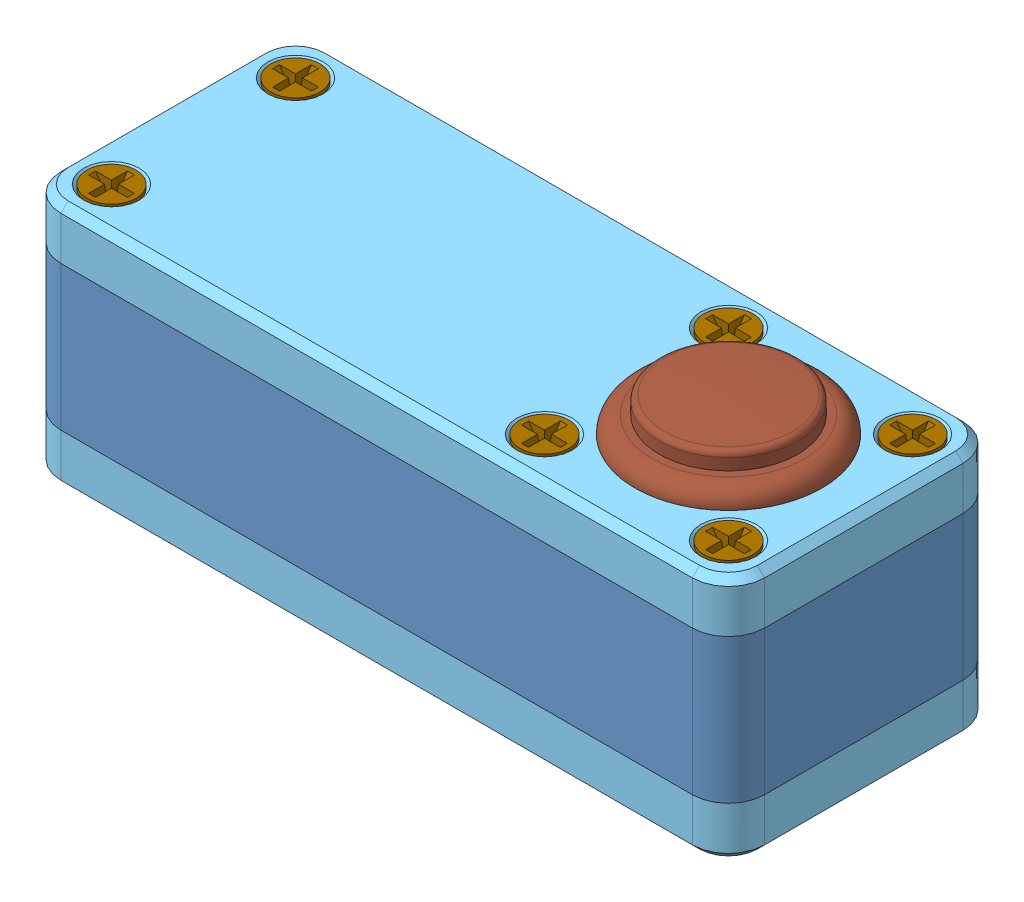
SolidWorks assembly Race clock 2, configuration Default. Lengths in mm.
Overall size (123.83 49.78 47.62).
28 component instances, 11 part files, 95 mates.
Components (placement in the parent):
- Basal planum^Race clock 2-1: Basal planum^Race clock 2 [Default] at (2.951 1.1176 33.45) size (123.83 25.4 47.62) (virtual)
- HUZZAH32-1: HUZZAH32 [Default] at (-76.7415 12.3402 44.88) size (50.8 8.14 22.86)
- OLED-1: OLED [Default] at (-76.7415 21.8017 44.88) size (50.8 10.6 22.86)
- LiPo 1200mAh-1: LiPo 1200mAh [Default] at (-81.1865 2.7151 50.468) size (59.69 4.78 34.04)
- Cover^Race clock 2-1: Cover^Race clock 2 [Default] at (7.6298 26.5176 -18.8777) size (123.82 8.92 47.62) (virtual)
- MicroUSB plug-1: MicroUSB plug [Default] at (-30.1071 14.2579 30.0083) size (13.87 3.05 6.88)
- MicroUSB jack-1: MicroUSB jack [Default] at (-95.3255 23.3299 39.9524) x (0 0 -1) z (-1 0 0) size (13 4.03 14.79)
- Tie rod^Race clock 2-1: Tie rod^Race clock 2 [Default] at (-89.4415 1.1176 17.2575) size (9.53 25.4 9.53) (virtual)
- Tie rod^Race clock 2-2: Tie rod^Race clock 2 [Default] at (19.1435 1.1176 17.2575) size (9.53 25.4 9.53) (virtual)
- Tie rod^Race clock 2-3: Tie rod^Race clock 2 [Default] at (-13.2415 1.1176 17.2575) size (9.53 25.4 9.53) (virtual)
- Tie rod^Race clock 2-4: Tie rod^Race clock 2 [Default] at (-89.4415 1.1176 49.6425) size (9.53 25.4 9.53) (virtual)
- Tie rod^Race clock 2-5: Tie rod^Race clock 2 [Default] at (-13.2415 1.1176 49.6425) size (9.53 25.4 9.53) (virtual)
- Tie rod^Race clock 2-6: Tie rod^Race clock 2 [Default] at (19.1435 1.1176 49.6425) size (9.53 25.4 9.53) (virtual)
- flat head screw_ai-1: flat head screw_ai [CR-FHMS 0.19-24x0.625x0.625-N] at (19.1435 -7.7978 17.2575) x (0 1 0) z (0 0 1) size (15.88 8.64 8.64)
- flat head screw_ai-2: flat head screw_ai [CR-FHMS 0.19-24x0.625x0.625-N] at (-13.2415 -7.7978 17.2575) x (0 1 0) z (0 0 1) size (15.88 8.64 8.64)
- flat head screw_ai-3: flat head screw_ai [CR-FHMS 0.19-24x0.625x0.625-N] at (-89.4415 -7.7978 17.2575) x (0 1 0) z (0 0 1) size (15.88 8.64 8.64)
- flat head screw_ai-4: flat head screw_ai [CR-FHMS 0.19-24x0.625x0.625-N] at (19.1435 -7.7978 49.6425) x (0 1 0) z (0 0 1) size (15.88 8.64 8.64)
- flat head screw_ai-5: flat head screw_ai [CR-FHMS 0.19-24x0.625x0.625-N] at (-13.2415 -7.7978 49.6425) x (0 1 0) z (0 0 1) size (15.88 8.64 8.64)
- flat head screw_ai-6: flat head screw_ai [CR-FHMS 0.19-24x0.625x0.625-N] at (-89.4415 -7.7978 49.6425) x (0 1 0) z (0 0 1) size (15.88 8.64 8.64)
- flat head screw_ai-7: flat head screw_ai [CR-FHMS 0.19-24x0.625x0.625-N] at (-89.4415 35.433 17.2575) x (0 -1 0) z (0 0 1) size (15.88 8.64 8.64)
- flat head screw_ai-8: flat head screw_ai [CR-FHMS 0.19-24x0.625x0.625-N] at (-13.2415 35.433 17.2575) x (0 -1 0) z (0 0 1) size (15.88 8.64 8.64)
- flat head screw_ai-9: flat head screw_ai [CR-FHMS 0.19-24x0.625x0.625-N] at (19.1435 35.433 17.2575) x (0 -1 0) z (0 0 1) size (15.88 8.64 8.64)
- flat head screw_ai-10: flat head screw_ai [CR-FHMS 0.19-24x0.625x0.625-N] at (-89.4415 35.433 49.6425) x (0 -1 0) z (0 0 1) size (15.88 8.64 8.64)
- flat head screw_ai-11: flat head screw_ai [CR-FHMS 0.19-24x0.625x0.625-N] at (-13.2415 35.433 49.6425) x (0 -1 0) z (0 0 1) size (15.88 8.64 8.64)
- flat head screw_ai-12: flat head screw_ai [CR-FHMS 0.19-24x0.625x0.625-N] at (19.1435 35.433 49.6425) x (0 -1 0) z (0 0 1) size (15.88 8.64 8.64)
- USB cover^Race clock 2-1: USB cover^Race clock 2 [Default] at (2.8575 23.2791 0) size (15.88 4.76 12.7) (virtual)
- Cover^Race clock 2-2: Cover^Race clock 2 [Bottom] at (7.6298 1.1176 85.7776) x (1 0 0) z (0 0 -1) size (123.82 8.92 47.62) (virtual)
- Arcade button-1: Arcade button [Default] at (2.951 35.433 33.45) x (-0.00267 0 -0.999996) z (0.999996 0 -0.00267) size (33 29.05 32.9)
Mates (geometry in assembly coordinates):
- Concentric1: concentric anti-aligned: cylinder of ? through (2.951 47.5536 33.45) axis (0 1 0) radius 5.925; cylinder of Basal planum^Race clock 2-1 through (2.951 26.5176 33.45) axis (0 -1 0) radius 6
- Concentric2: concentric aligned: cylinder of ? through (2.951 47.5536 33.45) axis (0 1 0) radius 4.3624; cylinder of ? through (2.951 54.2879 33.45) axis (0 1 0) radius 4.3656
- Coincident6: coincident aligned: plane of Basal planum^Race clock 2-1 through (2.951 1.8092 33.45) normal (0 0 1); plane of ? through (2.951 20.8592 33.45) normal (0 0 1)
- Coincident7: coincident aligned: plane of Basal planum^Race clock 2-1 through (2.951 1.8092 33.45) normal (1 0 0); plane of ? through (2.951 20.8592 33.45) normal (1 0 0)
- Coincident8: coincident anti-aligned: plane of Basal planum^Race clock 2-1 through (-47.849 20.8592 58.85) normal (0 1 0); plane of ? through (2.951 20.8592 33.45) normal (0 -1 0)
- Coincident9: coincident aligned: plane of HUZZAH32-1 through (-71.6615 19.2617 44.88) normal (0 0 1); plane of OLED-1 through (-71.6615 19.2617 44.88) normal (0 0 1)
- Coincident10: coincident aligned: plane of HUZZAH32-1 through (-71.6615 19.2617 42.34) normal (-1 0 0); plane of OLED-1 through (-71.6615 19.2617 42.34) normal (-1 0 0)
- Coincident11: coincident anti-aligned: plane of HUZZAH32-1 through (-76.7415 19.2617 44.88) normal (0 1 0); plane of OLED-1 through (-76.7415 19.2617 44.88) normal (0 -1 0)
- Concentric3: concentric aligned: cylinder of Basal planum^Race clock 2-1 through (-78.329 29.0576 63.93) axis (0 -1 0) radius 2.54; cylinder of ? through (-78.329 34.8996 63.93) axis (0 -1 0) radius 2.54
- Concentric4: concentric aligned: cylinder of Basal planum^Race clock 2-1 through (33.431 29.0576 2.97) axis (0 -1 0) radius 2.54; cylinder of ? through (33.431 34.8996 2.97) axis (0 -1 0) radius 2.54
- Coincident12: coincident anti-aligned: plane of Basal planum^Race clock 2-1 through (-73.249 29.0576 58.85) normal (0 1 0); plane of ? through (-73.249 29.0576 58.85) normal (0 -1 0)
- Coincident13: coincident anti-aligned: plane of ? through (2.951 16.3576 33.45) normal (0 1 0); plane of Basal planum^Race clock 2-1 through (6.761 16.3576 33.45) normal (0 -1 0)
- Concentric5: concentric aligned: cylinder of Basal planum^Race clock 2-1 through (-78.329 29.0576 63.93) axis (0 -1 0) radius 2.54; cylinder of ? through (-78.329 1.1176 63.93) axis (0 -1 0) radius 2.54
- Concentric6: concentric aligned: cylinder of Basal planum^Race clock 2-1 through (33.431 29.0576 2.97) axis (0 -1 0) radius 2.54; cylinder of ? through (33.431 1.1176 2.97) axis (0 -1 0) radius 2.54
- Coincident14: coincident anti-aligned: plane of Basal planum^Race clock 2-1 through (-73.249 1.1176 58.85) normal (0 -1 0); plane of ? through (-73.249 1.1176 58.85) normal (0 1 0)
- Parallel1: parallel anti-aligned: plane of ? through (6.9324 15.0876 39.7809) normal (0 0 1); plane of Basal planum^Race clock 2-1 through (-16.099 10.0076 41.07) normal (0 0 -1)
- Width5: width anti-aligned: plane of Basal planum^Race clock 2-1 through (-74.2015 10.0076 19.48) normal (0 0 1); plane of Basal planum^Race clock 2-1 through (-74.2015 10.0076 47.42) normal (0 0 -1); plane of HUZZAH32-1 through (-71.6615 19.2617 22.02) normal (0 0 -1); plane of HUZZAH32-1 through (-71.6615 19.2617 44.88) normal (0 0 1)
- Width6: width anti-aligned: plane of Basal planum^Race clock 2-1 through (-23.4015 10.0076 24.56) normal (-1 0 0); plane of Basal planum^Race clock 2-1 through (-79.2815 10.0076 24.56) normal (1 0 0); plane of HUZZAH32-1 through (-25.9415 13.9277 42.34) normal (1 0 0); plane of HUZZAH32-1 through (-76.7415 13.9277 42.34) normal (-1 0 0)
- Width7: width anti-aligned: plane of Basal planum^Race clock 2-1 through (-19.5915 7.4676 18.21) normal (-1 0 0); plane of Basal planum^Race clock 2-1 through (-83.0915 7.4676 18.21) normal (1 0 0); plane of LiPo 1200mAh-1 through (-21.4965 7.4903 50.468) normal (1 0 0); plane of LiPo 1200mAh-1 through (-81.1865 7.4903 50.468) normal (-1 0 0)
- Width8: width anti-aligned: plane of Basal planum^Race clock 2-1 through (-79.2815 7.4676 14.4) normal (0 0 1); plane of Basal planum^Race clock 2-1 through (-79.2815 7.4676 52.5) normal (0 0 -1); plane of LiPo 1200mAh-1 through (-81.1865 7.4903 16.432) normal (0 0 -1); plane of LiPo 1200mAh-1 through (-81.1865 7.4903 50.468) normal (0 0 1)
- Coincident15: coincident aligned: plane of Basal planum^Race clock 2-1 through (26.7635 26.5176 50.9125) normal (1 0 0); plane of Cover^Race clock 2-1 through (26.7635 35.433 50.9125) normal (1 0 0)
- Coincident16: coincident aligned: plane of Basal planum^Race clock 2-1 through (-90.7115 26.5176 9.6375) normal (0 0 -1); plane of Cover^Race clock 2-1 through (-90.7115 35.433 9.6375) normal (0 0 -1)
- Coincident17: coincident anti-aligned: plane of Basal planum^Race clock 2-1 through (-90.7115 26.5176 50.9125) normal (0 1 0); plane of Cover^Race clock 2-1 through (-90.7115 26.5176 15.9875) normal (0 -1 0)
- Coincident18: coincident aligned: plane of Basal planum^Race clock 2-1 through (33.431 26.5176 57.58) normal (1 0 0); plane of ? through (33.431 -8.4074 57.58) normal (1 0 0)
- Coincident19: coincident aligned: plane of Basal planum^Race clock 2-1 through (-93.569 26.5176 2.97) normal (0 0 -1); plane of ? through (27.081 -8.4074 2.97) normal (0 0 -1)
- Coincident20: coincident anti-aligned: plane of Basal planum^Race clock 2-1 through (-93.569 1.1176 57.58) normal (0 -1 0); plane of ? through (-93.569 1.1176 57.58) normal (0 1 0)
- Width9: width anti-aligned: plane of HUZZAH32-1 through (-31.5295 16.3915 37.26) normal (0 0 1); plane of HUZZAH32-1 through (-31.5295 16.3915 29.64) normal (0 0 -1); plane of MicroUSB plug-1 through (-30.1071 14.2579 30.0083) normal (0 0 -1); plane of MicroUSB plug-1 through (-30.1071 14.2579 36.8917) normal (0 0 1)
- Width10: width aligned: plane of HUZZAH32-1 through (-76.7415 16.3915 44.88) normal (0 1 0); plane of HUZZAH32-1 through (-74.2015 13.9277 42.34) normal (0 1 0); plane of MicroUSB plug-1 through (-30.1071 16.0613 36.8917) normal (0 1 0); plane of MicroUSB plug-1 through (-22.9443 14.2579 36.8917) normal (0 -1 0)
- Coincident21: coincident anti-aligned: plane of HUZZAH32-1 through (-25.9415 13.9277 42.34) normal (1 0 0); plane of MicroUSB plug-1 through (-25.9415 14.2579 30.0083) normal (-1 0 0)
- Coincident25: coincident anti-aligned: plane of Basal planum^Race clock 2-1 through (2.951 21.6916 33.45) normal (0 1 0); plane of MicroUSB jack-1 through (-95.3255 21.6916 39.9524) normal (0 -1 0)
- Concentric9: concentric aligned: cylinder of Basal planum^Race clock 2-1 through (-88.4255 7.4676 29.0304) axis (0 1 0) radius 1.524; cylinder of MicroUSB jack-1 through (-88.4255 21.6916 29.0304) axis (0 1 0) radius 1.5
- Concentric10: concentric aligned: cylinder of Basal planum^Race clock 2-1 through (-88.4255 7.4676 37.8696) axis (0 1 0) radius 1.524; cylinder of MicroUSB jack-1 through (-88.4255 21.6916 37.8696) axis (0 1 0) radius 1.5
- Concentric11: concentric aligned: cylinder of Basal planum^Race clock 2-1 through (-89.4415 26.5176 17.2575) axis (0 -1 0) radius 4.7625; cylinder of Tie rod^Race clock 2-1 through (-89.4415 26.5176 17.2575) axis (0 -1 0) radius 4.7625
- Concentric12: concentric aligned: cylinder of Basal planum^Race clock 2-1 through (-13.2415 26.5176 17.2575) axis (0 -1 0) radius 4.7625; cylinder of Tie rod^Race clock 2-3 through (-13.2415 26.5176 17.2575) axis (0 -1 0) radius 4.7625
- Concentric13: concentric aligned: cylinder of Basal planum^Race clock 2-1 through (19.1435 26.5176 17.2575) axis (0 -1 0) radius 4.7625; cylinder of Tie rod^Race clock 2-2 through (19.1435 26.5176 17.2575) axis (0 -1 0) radius 4.7625
- Concentric14: concentric aligned: cylinder of Basal planum^Race clock 2-1 through (-89.4415 26.5176 49.6425) axis (0 -1 0) radius 4.7625; cylinder of Tie rod^Race clock 2-4 through (-89.4415 26.5176 49.6425) axis (0 -1 0) radius 4.7625
- Concentric15: concentric aligned: cylinder of Basal planum^Race clock 2-1 through (-13.2415 26.5176 49.6425) axis (0 -1 0) radius 4.7625; cylinder of Tie rod^Race clock 2-5 through (-13.2415 26.5176 49.6425) axis (0 -1 0) radius 4.7625
- Concentric16: concentric aligned: cylinder of Basal planum^Race clock 2-1 through (19.1435 26.5176 49.6425) axis (0 -1 0) radius 4.7625; cylinder of Tie rod^Race clock 2-6 through (19.1435 26.5176 49.6425) axis (0 -1 0) radius 4.7625
- Coincident26: coincident aligned: plane of Basal planum^Race clock 2-1 through (-90.7115 26.5176 50.9125) normal (0 1 0); plane of Tie rod^Race clock 2-1 through (-89.4415 26.5176 17.2575) normal (0 1 0)
- Coincident27: coincident aligned: plane of Basal planum^Race clock 2-1 through (-90.7115 26.5176 50.9125) normal (0 1 0); plane of Tie rod^Race clock 2-4 through (-89.4415 26.5176 49.6425) normal (0 1 0)
- Coincident28: coincident aligned: plane of Basal planum^Race clock 2-1 through (-90.7115 26.5176 50.9125) normal (0 1 0); plane of Tie rod^Race clock 2-5 through (-13.2415 26.5176 49.6425) normal (0 1 0)
- Coincident29: coincident aligned: plane of Basal planum^Race clock 2-1 through (-90.7115 26.5176 50.9125) normal (0 1 0); plane of Tie rod^Race clock 2-3 through (-13.2415 26.5176 17.2575) normal (0 1 0)
- Coincident30: coincident aligned: plane of Basal planum^Race clock 2-1 through (-90.7115 26.5176 50.9125) normal (0 1 0); plane of Tie rod^Race clock 2-2 through (19.1435 26.5176 17.2575) normal (0 1 0)
- Coincident31: coincident aligned: plane of Basal planum^Race clock 2-1 through (-90.7115 26.5176 50.9125) normal (0 1 0); plane of Tie rod^Race clock 2-6 through (19.1435 26.5176 49.6425) normal (0 1 0)
- Concentric17: concentric aligned: cylinder of Cover^Race clock 2-1 through (-89.4415 35.433 17.2575) axis (0 1 0) radius 2.5527; cylinder of flat head screw_ai-7 through (-89.4415 41.783 17.2575) axis (0 1 0) radius 2.413
- Concentric18: concentric aligned: cylinder of Cover^Race clock 2-1 through (-13.2415 35.433 17.2575) axis (0 1 0) radius 2.5527; cylinder of flat head screw_ai-8 through (-13.2415 41.783 17.2575) axis (0 1 0) radius 2.413
- Concentric19: concentric aligned: cylinder of Cover^Race clock 2-1 through (19.1435 35.433 17.2575) axis (0 1 0) radius 2.5527; cylinder of flat head screw_ai-9 through (19.1435 41.783 17.2575) axis (0 1 0) radius 2.413
- Concentric20: concentric aligned: cylinder of Cover^Race clock 2-1 through (-89.4415 35.433 49.6425) axis (0 1 0) radius 2.5527; cylinder of flat head screw_ai-10 through (-89.4415 41.783 49.6425) axis (0 1 0) radius 2.413
- Concentric21: concentric aligned: cylinder of Cover^Race clock 2-1 through (-13.2415 35.433 49.6425) axis (0 1 0) radius 2.5527; cylinder of flat head screw_ai-11 through (-13.2415 41.783 49.6425) axis (0 1 0) radius 2.413
- Concentric22: concentric aligned: cylinder of Cover^Race clock 2-1 through (19.1435 35.433 49.6425) axis (0 1 0) radius 2.5527; cylinder of flat head screw_ai-12 through (19.1435 41.783 49.6425) axis (0 1 0) radius 2.413
- Coincident32: coincident aligned: plane of Cover^Race clock 2-1 through (-90.7115 35.433 15.9875) normal (0 1 0); plane of flat head screw_ai-7 through (-89.4415 35.433 17.2575) normal (0 1 0)
- Coincident33: coincident aligned: plane of Cover^Race clock 2-1 through (-90.7115 35.433 15.9875) normal (0 1 0); plane of flat head screw_ai-10 through (-89.4415 35.433 49.6425) normal (0 1 0)
- Coincident35: coincident aligned: plane of Cover^Race clock 2-1 through (-90.7115 35.433 15.9875) normal (0 1 0); plane of flat head screw_ai-11 through (-13.2415 35.433 49.6425) normal (0 1 0)
- Coincident36: coincident aligned: plane of Cover^Race clock 2-1 through (-90.7115 35.433 15.9875) normal (0 1 0); plane of flat head screw_ai-8 through (-13.2415 35.433 17.2575) normal (0 1 0)
- Coincident37: coincident aligned: plane of Cover^Race clock 2-1 through (-90.7115 35.433 15.9875) normal (0 1 0); plane of flat head screw_ai-9 through (19.1435 35.433 17.2575) normal (0 1 0)
- Coincident38: coincident aligned: plane of Cover^Race clock 2-1 through (-90.7115 35.433 15.9875) normal (0 1 0); plane of flat head screw_ai-12 through (19.1435 35.433 49.6425) normal (0 1 0)
- Concentric23: concentric aligned: cylinder of ? through (25.811 -8.4074 10.59) axis (0 -1 0) radius 2.5527; cylinder of flat head screw_ai-1 through (25.811 -14.7574 10.59) axis (0 -1 0) radius 2.413
- Concentric24: concentric aligned: cylinder of ? through (-19.909 -8.4074 10.59) axis (0 -1 0) radius 2.5527; cylinder of flat head screw_ai-2 through (-19.909 -14.7574 10.59) axis (0 -1 0) radius 2.413
- Concentric25: concentric aligned: cylinder of ? through (-92.299 -8.4074 10.59) axis (0 -1 0) radius 2.5527; cylinder of flat head screw_ai-3 through (-92.299 -14.7574 10.59) axis (0 -1 0) radius 2.413
- Concentric26: concentric aligned: cylinder of ? through (25.811 -8.4074 56.31) axis (0 -1 0) radius 2.5527; cylinder of flat head screw_ai-4 through (25.811 -14.7574 56.31) axis (0 -1 0) radius 2.413
- Concentric27: concentric aligned: cylinder of ? through (-19.909 -8.4074 56.31) axis (0 -1 0) radius 2.5527; cylinder of flat head screw_ai-5 through (-19.909 -14.7574 56.31) axis (0 -1 0) radius 2.413
- Concentric28: concentric aligned: cylinder of ? through (-92.299 -8.4074 56.31) axis (0 -1 0) radius 2.5527; cylinder of flat head screw_ai-6 through (-92.299 -14.7574 56.31) axis (0 -1 0) radius 2.413
- Coincident39: coincident aligned: plane of ? through (-93.569 -8.4074 57.58) normal (0 -1 0); plane of flat head screw_ai-1 through (25.811 -8.4074 10.59) normal (0 -1 0)
- Coincident41: coincident aligned: plane of ? through (-93.569 -8.4074 57.58) normal (0 -1 0); plane of flat head screw_ai-5 through (-19.909 -8.4074 56.31) normal (0 -1 0)
- Coincident42: coincident aligned: plane of ? through (-93.569 -8.4074 57.58) normal (0 -1 0); plane of flat head screw_ai-2 through (-19.909 -8.4074 10.59) normal (0 -1 0)
- Coincident43: coincident aligned: plane of ? through (-93.569 -8.4074 57.58) normal (0 -1 0); plane of flat head screw_ai-3 through (-92.299 -8.4074 10.59) normal (0 -1 0)
- Coincident44: coincident aligned: plane of ? through (-93.569 -8.4074 57.58) normal (0 -1 0); plane of flat head screw_ai-6 through (-92.299 -8.4074 56.31) normal (0 -1 0)
- Concentric29: concentric anti-aligned: cylinder of Basal planum^Race clock 2-1 through (-88.4255 7.4676 29.0304) axis (0 1 0) radius 1.524; cylinder of USB cover^Race clock 2-1 through (-88.4255 26.4541 29.0304) axis (0 -1 0) radius 1.524
- Concentric30: concentric anti-aligned: cylinder of Basal planum^Race clock 2-1 through (-88.4255 7.4676 37.8696) axis (0 1 0) radius 1.524; cylinder of USB cover^Race clock 2-1 through (-88.4255 26.4541 37.8696) axis (0 -1 0) radius 1.524
- Coincident45: coincident anti-aligned: plane of Basal planum^Race clock 2-1 through (2.951 21.6916 33.45) normal (0 1 0); plane of USB cover^Race clock 2-1 through (2.8575 21.6916 0) normal (0 -1 0)
- Coincident46: coincident anti-aligned: plane of Basal planum^Race clock 2-1 through (-90.7115 1.1176 50.9125) normal (0 -1 0); plane of Cover^Race clock 2-2 through (-90.7115 1.1176 50.9125) normal (0 1 0)
- Coincident47: coincident aligned: plane of Basal planum^Race clock 2-1 through (26.7635 26.5176 50.9125) normal (1 0 0); plane of Cover^Race clock 2-2 through (26.7635 -7.7978 15.9875) normal (1 0 0)
- Coincident48: coincident aligned: plane of Basal planum^Race clock 2-1 through (-90.7115 26.5176 9.6375) normal (0 0 -1); plane of Cover^Race clock 2-2 through (-90.7115 -7.7978 9.6375) normal (0 0 -1)
- Concentric31: concentric aligned: cylinder of flat head screw_ai-6 through (-89.4415 -14.1478 49.6425) axis (0 -1 0) radius 2.413; cylinder of Cover^Race clock 2-2 through (-89.4415 -7.7978 49.6425) axis (0 -1 0) radius 2.5527
- Concentric32: concentric aligned: cylinder of flat head screw_ai-3 through (-89.4415 -14.1478 17.2575) axis (0 -1 0) radius 2.413; cylinder of Cover^Race clock 2-2 through (-89.4415 -7.7978 17.2575) axis (0 -1 0) radius 2.5527
- Concentric33: concentric aligned: cylinder of flat head screw_ai-2 through (-13.2415 -14.1478 17.2575) axis (0 -1 0) radius 2.413; cylinder of Cover^Race clock 2-2 through (-13.2415 -7.7978 17.2575) axis (0 -1 0) radius 2.5527
- Concentric34: concentric aligned: cylinder of flat head screw_ai-1 through (19.1435 -14.1478 17.2575) axis (0 -1 0) radius 2.413; cylinder of Cover^Race clock 2-2 through (19.1435 -7.7978 17.2575) axis (0 -1 0) radius 2.5527
- Concentric35: concentric aligned: cylinder of flat head screw_ai-4 through (19.1435 -14.1478 49.6425) axis (0 -1 0) radius 2.413; cylinder of Cover^Race clock 2-2 through (19.1435 -7.7978 49.6425) axis (0 -1 0) radius 2.5527
- Concentric36: concentric aligned: cylinder of flat head screw_ai-5 through (-13.2415 -14.1478 49.6425) axis (0 -1 0) radius 2.413; cylinder of Cover^Race clock 2-2 through (-13.2415 -7.7978 49.6425) axis (0 -1 0) radius 2.5527
- Coincident49: coincident aligned: plane of flat head screw_ai-6 through (-89.4415 -7.7978 49.6425) normal (0 -1 0); plane of Cover^Race clock 2-2 through (-90.7115 -7.7978 50.9125) normal (0 -1 0)
- Coincident50: coincident aligned: plane of flat head screw_ai-5 through (-13.2415 -7.7978 49.6425) normal (0 -1 0); plane of Cover^Race clock 2-2 through (-90.7115 -7.7978 50.9125) normal (0 -1 0)
- Coincident51: coincident aligned: plane of flat head screw_ai-1 through (19.1435 -7.7978 17.2575) normal (0 -1 0); plane of Cover^Race clock 2-2 through (-90.7115 -7.7978 50.9125) normal (0 -1 0)
- Coincident52: coincident aligned: plane of flat head screw_ai-2 through (-13.2415 -7.7978 17.2575) normal (0 -1 0); plane of Cover^Race clock 2-2 through (-90.7115 -7.7978 50.9125) normal (0 -1 0)
- Coincident53: coincident aligned: plane of flat head screw_ai-3 through (-89.4415 -7.7978 17.2575) normal (0 -1 0); plane of Cover^Race clock 2-2 through (-90.7115 -7.7978 50.9125) normal (0 -1 0)
- Coincident54: coincident aligned: plane of flat head screw_ai-4 through (19.1435 -7.7978 49.6425) normal (0 -1 0); plane of Cover^Race clock 2-2 through (-90.7115 -7.7978 50.9125) normal (0 -1 0)
- Concentric37: concentric anti-aligned: cylinder of Basal planum^Race clock 2-1 through (22.001 1.1176 33.45) axis (0 1 0) radius 4.7625; cylinder of ? through (22.001 39.1541 33.45) axis (0 -1 0) radius 1.8986
- LimitDistance1: limit distance = 0 mm anti-aligned: plane of ? through (2.951 41.6941 33.45) normal (0 -1 0); plane of ? through (-1.4115 41.6941 33.45) normal (0 1 0)
- Coincident55: coincident anti-aligned: plane of ? through (22.001 39.1541 33.45) normal (0 -1 0); plane of ? through (20.2179 39.1541 33.45) normal (0 1 0)
- Concentric38: concentric aligned: cylinder of ? through (22.001 39.1541 33.45) axis (0 -1 0) radius 1.8986; cylinder of ? through (22.001 -13.2969 33.45) axis (0 -1 0) radius 2.413
- Coincident58: coincident anti-aligned: plane of ? through (-6.574 39.1541 49.9477) normal (0 -1 0); plane of ? through (-8.3571 39.1541 49.9477) normal (0 1 0)
- Concentric41: concentric aligned: cylinder of ? through (-6.574 39.1541 49.9477) axis (0 -1 0) radius 1.8986; cylinder of ? through (-6.574 -13.2969 49.9477) axis (0 -1 0) radius 2.413
- Coincident59: coincident anti-aligned: plane of ? through (-6.574 39.1541 16.9522) normal (0 -1 0); plane of ? through (-8.3571 39.1541 16.9522) normal (0 1 0)
- Concentric42: concentric aligned: cylinder of ? through (-6.574 39.1541 16.9522) axis (0 -1 0) radius 1.8986; cylinder of ? through (-6.574 -13.2969 16.9522) axis (0 -1 0) radius 2.413
- Concentric43: concentric anti-aligned: cylinder of Cover^Race clock 2-1 through (2.951 35.433 33.45) axis (0 -1 0) radius 15; cylinder of Arcade button-1 through (2.951 43.404 33.45) axis (0 1 0) radius 14.9
- Coincident60: coincident anti-aligned: plane of Cover^Race clock 2-1 through (-90.7115 35.433 15.9875) normal (0 1 0); plane of Arcade button-1 through (2.907 35.433 17) normal (0 -1 0)
